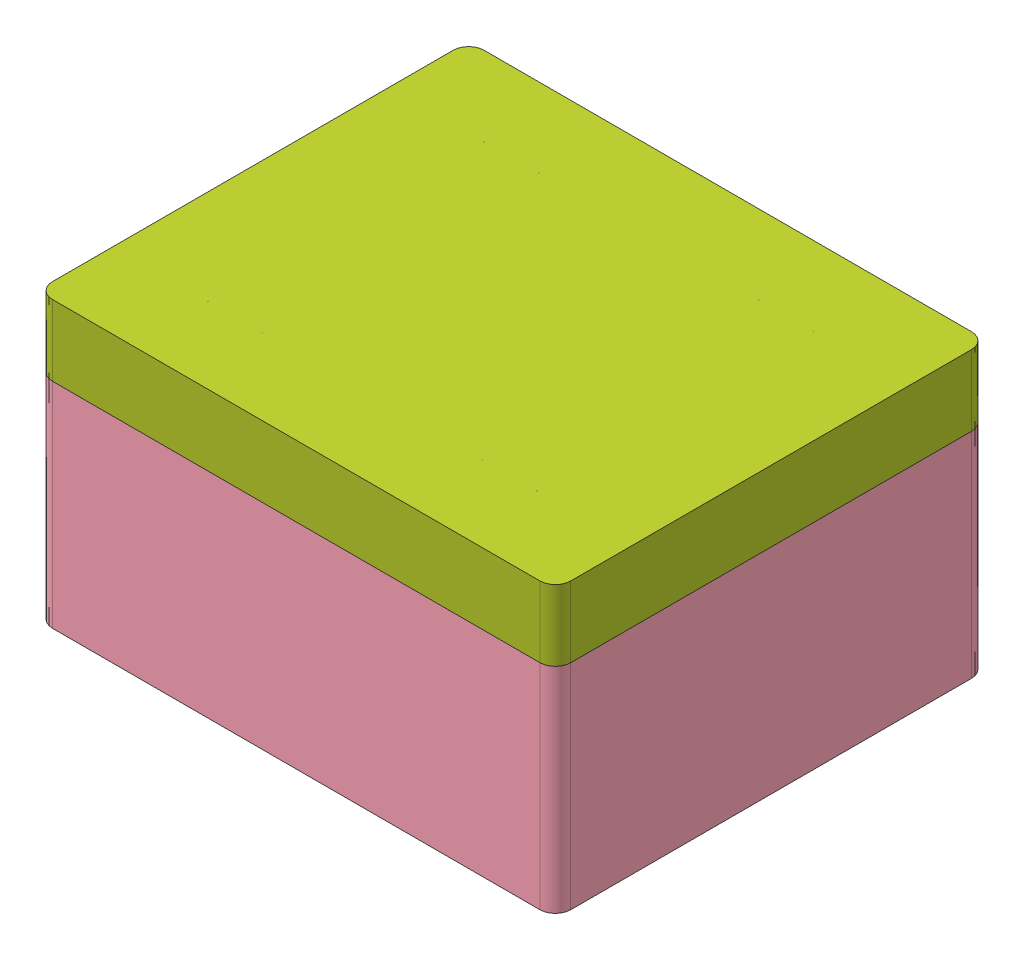
SolidWorks assembly Battery_Mount, configuration Default. Lengths in mm.
Overall size (428.6 235.47 356.89).
11 component instances, 7 part files, 0 mates.
Components (placement in the parent):
- Battery Enclosure 16122020-1: Battery Enclosure 16122020 [Default] at (188.7779 231.3308 742.0881) x (1 0 0) z (0 1 0) size (428.6 356.89 235.47)
  - GoalZero-2: GoalZero [Default] at (-109.4755 365.738 -45.5585) x (-1 0 0) z (0 1 0) size (285.75 147.32 193.04)
  - ACAdapter-1: ACAdapter [Default] at (-158.3705 515.1784 45.3602) x (0 0 -1) z (-1 0 0) size (83.1 32.5 42.8)
  - ACAdapter-2: ACAdapter [Default] at (-211.7105 482.6784 45.3602) x (0 0 -1) z (1 0 0) size (83.1 32.5 42.8)
  - 8961K107_MOUNTING ADAPTERS FOR DIN RAIL-1: 8961K107_MOUNTING ADAPTERS FOR DIN RAIL [8961K107] at (-109.4755 327.7384 -45.5585) x (0 0 1) z (1 0 0) size (8 51.36 75)
  - 8961K107_MOUNTING ADAPTERS FOR DIN RAIL-2: 8961K107_MOUNTING ADAPTERS FOR DIN RAIL [8961K107] at (-109.4755 407.3709 -45.5585) x (0 0 1) z (1 0 0) size (8 51.36 75)
  - 1507 Bottom Tub Battery 1-1: 1507 Bottom Tub Battery 1 [Default] at (-109.4755 402.4084 96.5875) x (1 0 0) z (0 -1 0) size (428.6 178.19 356.89)
  - 8961K93_MOUNTING ADAPTERS FOR DIN RAIL-2-4: 8961K93_MOUNTING ADAPTERS FOR DIN RAIL-2 [8961K93] at (-287.2755 428.5384 -55.5585) x (0 0 -1) z (1 0 0) size (7.5 35 355.6)
  - 8961K93_MOUNTING ADAPTERS FOR DIN RAIL-2-5: 8961K93_MOUNTING ADAPTERS FOR DIN RAIL-2 [8961K93] at (-287.2755 348.9059 -55.5585) x (0 0 -1) z (1 0 0) size (7.5 35 355.6)
  - Back_Plate-1: Back_Plate [Default] at (-109.4755 402.4084 -68.2585) x (-1 0 0) z (0 1 0) size (355.6 12.7 254)
  - 1507 Top Tub-1: 1507 Top Tub [Default] at (-109.4755 399.895 96.5875) x (-1 0 0) z (0 1 0) size (428.6 59.13 356.89)
